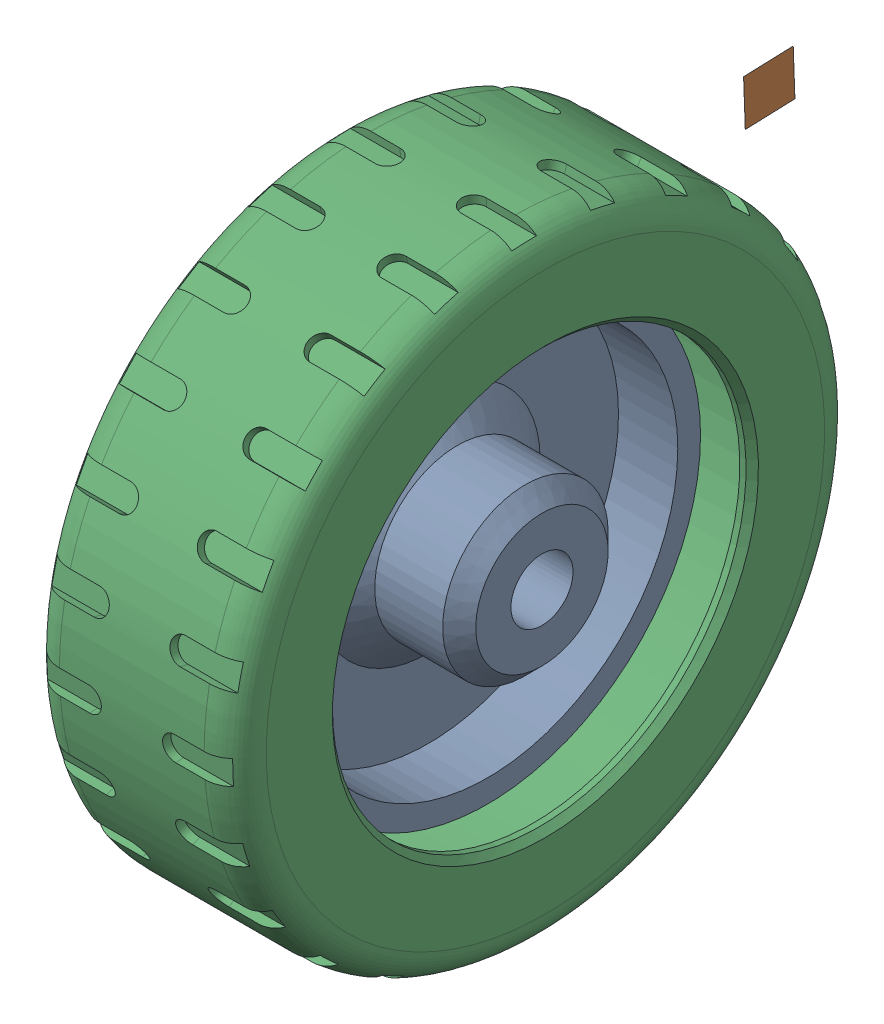
SolidWorks assembly Колесо в всборе, configuration Default. Lengths in mm.
Overall size (50 156.09 156.09).
2 component instances, 2 part files, 3 mates.
Components (placement in the parent):
- Обод колеса-1: Обод колеса [Default] at (49.1248 49.7905 75.0677) size (49.16 103.37 103.37)
- Шина-1: Шина [Default] at (214.6046 49.7905 75.0677) x (1 0 0) z (0 -0.036229 0.999344) size (50 150.73 162.36)
Mates (geometry in assembly coordinates):
- Concentric1: concentric: circle of Part машина 7-1; circle of Part машина 7_1-1
- Coincident1: coincident: plane of Part машина 7-1 through (27.4621 101.4763 75.0677) normal (-1 0 0); plane of Part машина 7_1-1 through (27.4621 99.7576 76.8792) normal (-1 0 0)
- Parallel2: parallel aligned: plane of Part машина 7-1 through (34.3684 39.0463 80.7622) normal (0 -0.883571 0.468297); plane of Part машина 7_1-1 through (42.0528 -14.7102 109.2534) normal (0 -0.883571 0.468297)
